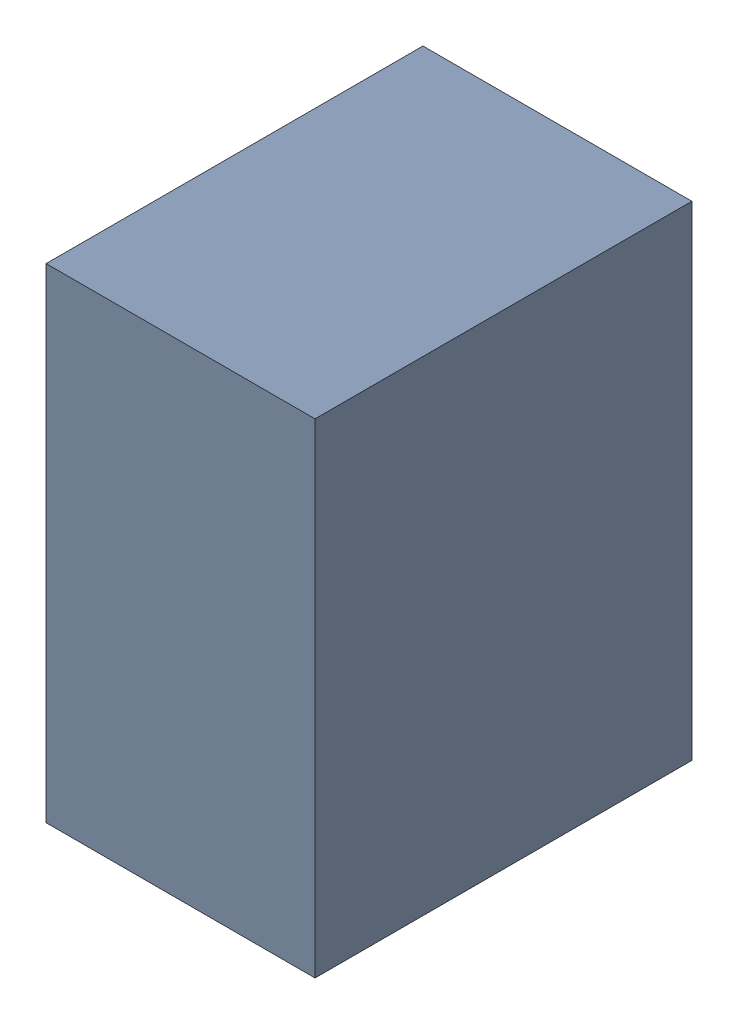
SolidWorks assembly C46, configuration Default. Lengths in mm.
Overall size (1 1.8 1.4).
3 component instances, 2 part files, 0 mates.
Components (placement in the parent):
- 1088883208-1: 1088883208 [Default] at (16.2924 2.7082 -3.044) size (1 1.8 1.4)
  - Extruded-45-1: Extruded-45 [Default] at origin size (1 1.8 1.4)
- C0603-1: C0603 [Default] at (16.6925 3.5082 -1.644) x (0 -1 0) z (1 0 0) size (1.6 0.5 0.8)
